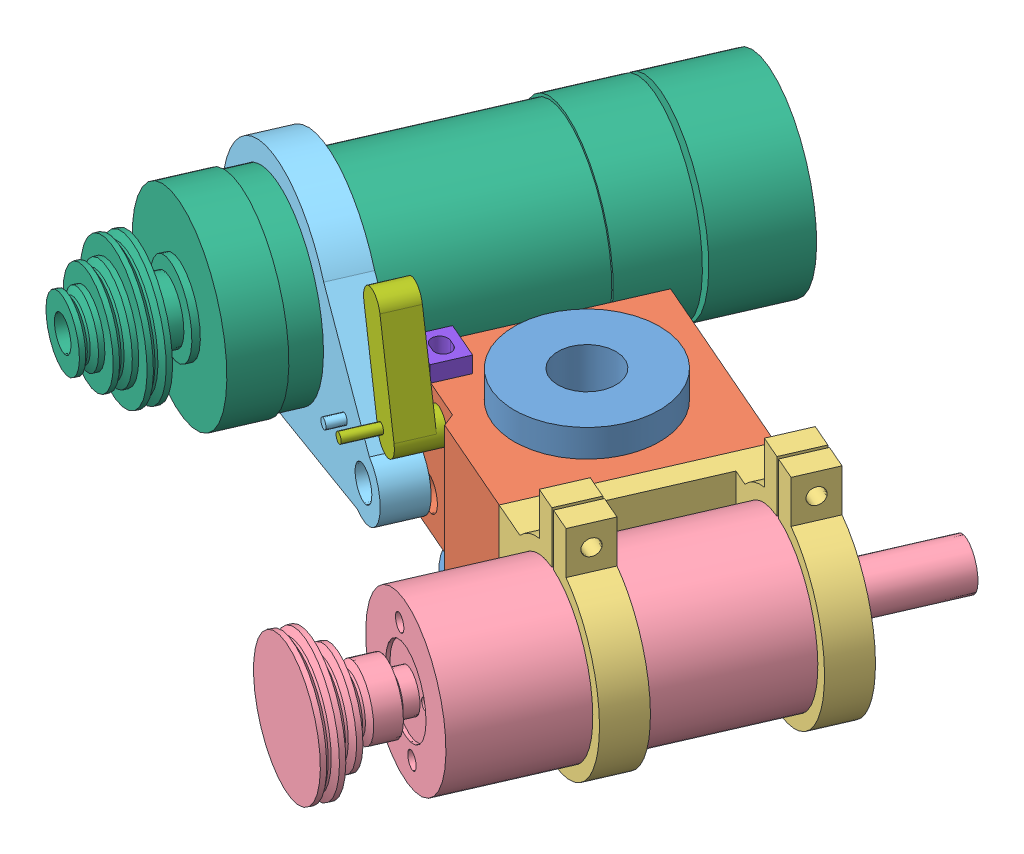
SolidWorks assembly Grinder Assembly, configuration Default. Lengths in mm.
Overall size (249.2 115.45 235.8).
8 component instances, 8 part files, 20 mates.
Components (placement in the parent):
- Center Boss-1: Center Boss [Default] at origin size (65 60 65)
- Grinder Base-1: Grinder Base [Default] at (0 11.5 0) x (-0.916958 0 -0.398985) z (0.398985 0 -0.916958) size (63 40 65)
- Spindle Clamp-1: Spindle Clamp [Default] at (56.9256 31.5 24.7694) x (0.916958 0 0.398985) z (-0.398985 0 0.916958) size (60 68 65)
- Spindle and Bearings and pulleys-1: Spindle and Bearings and pulleys [Default] at (50.1097 31.5 40.4339) x (-0.204426 0.974832 -0.08895) z (0.398985 0 -0.916958) size (48 48 160)
- Powered Spindle Bracket-1: Powered Spindle Bracket [Default] at (-83.8503 46.5162 12.0453) x (0.516913 -0.825961 0.224918) z (0.398985 0 -0.916958) size (88.55 75.05 17)
- Powered Spindle-2: Powered Spindle [Default] at (-70.717 46.5162 -18.1381) x (0.501751 0.837008 0.218321) z (-0.398985 0 0.916958) size (56.7 56.7 169.2)
- Cam Shaft-1: Cam Shaft [Default] at (-21.1566 43.5 14.7868) x (0.881169 0.276651 0.383413) z (-0.398985 0 0.916958) size (10 40.47 30)
- Belt tension-1: Belt tension [Default] at (-32.2527 51.5 12.8486) x (0.398985 0 -0.916958) z (0.916958 0 0.398985) size (15 5 12)
Mates (geometry in assembly coordinates):
- Concentric1: concentric anti-aligned: cylinder of Center Boss-1 through (0 60 0) axis (0 -1 0) radius 22.5; cylinder of Grinder Base-1 through (0 11.499 0) axis (0 1 0) radius 22.5
- Coincident1: coincident: plane of Grinder Base-1 through (25.2163 11.5 10.9721) normal (0.916958 0 0.398985); plane of Spindle Clamp-1 through (12.2493 31.5 40.7732) normal (-0.916958 0 -0.398985)
- Coincident2: coincident aligned: plane of Grinder Base-1 through (42.7681 51.5 -16.8341) normal (0.398985 0 -0.916958); plane of Spindle Clamp-1 through (69.8926 31.5 -5.0318) normal (0.398985 0 -0.916958)
- Coincident3: coincident aligned: plane of Grinder Base-1 through (0 51.5 0) normal (0 1 0); plane of Spindle Clamp-1 through (43.9586 51.5 54.5705) normal (0 1 0)
- Distance1: distance = 5.5 mm anti-aligned: plane of Grinder Base-1 through (0 11.5 0) normal (0 -1 0); plane of Center Boss-1 through (0 6 0) normal (0 1 0)
- Concentric2: concentric anti-aligned: cylinder of Spindle Clamp-1 through (43.9586 31.5 54.5705) axis (0.398985 0 -0.916958) radius 24; cylinder of Spindle and Bearings and pulleys-1 through (70.0589 31.5 -5.414) axis (-0.398985 0 0.916958) radius 24
- Concentric3: concentric: cylinder of Grinder Base-1 through (-38.3864 21.5 31.8275) axis (0.398985 0 -0.916958) radius 5; cylinder of Powered Spindle Bracket-1 through (-33.5986 21.5 20.824) axis (-0.398985 0 0.916958) radius 5
- Coincident5: coincident: plane of Grinder Base-1 through (-38.3864 21.5 31.8275) normal (-0.398985 0 0.916958); plane of Powered Spindle Bracket-1 through (-87.9388 47.5705 10.2663) normal (-0.398985 0 0.916958)
- Parallel1: parallel aligned: plane of Powered Spindle Bracket-1 through (-83.8503 46.5162 12.0453) normal (-0.398985 0 0.916958); plane of Powered Spindle-2 through (-102.6539 53.3561 29.0371) normal (-0.398985 0 0.916958)
- Concentric5: concentric aligned: cylinder of Powered Spindle Bracket-1 through (-79.0625 46.5162 1.0418) axis (-0.398985 0 0.916958) radius 27.5; cylinder of Powered Spindle-2 through (-109.3987 46.5162 70.7613) axis (-0.398985 0 0.916958) radius 27.5
- Coincident7: coincident aligned: plane of Spindle and Bearings and pulleys-1 through (23.4583 32.6147 113.9013) normal (-0.398985 0 0.916958); plane of Powered Spindle-2 through (-111.7072 51.9881 55.0883) normal (-0.398985 0 0.916958)
- Belt Length 125/135: limit distance = 135 mm: line of Powered Spindle-2 through (-104.0322 46.5162 58.4278) axis (0.398985 0 -0.916958); line of Spindle and Bearings and pulleys-1 through (18.9889 31.5 111.9565) axis (0.398985 0 -0.916958)
- LimitDistance2: limit distance = 0.4169 mm aligned: plane of Spindle and Bearings and pulleys-1 through (70.0589 31.5 -5.414) normal (0.398985 0 -0.916958); plane of Spindle Clamp-1 through (69.8926 31.5 -5.0318) normal (0.398985 0 -0.916958)
- LimitDistance4: limit distance = 8.4831 mm anti-aligned: plane of Powered Spindle-2 through (-108.9936 62.0291 10.3563) normal (0.398985 0 -0.916958); plane of Powered Spindle Bracket-1 through (-83.8503 46.5162 12.0453) normal (-0.398985 0 0.916958)
- Concentric9: concentric anti-aligned: cylinder of Grinder Base-1 through (-21.1566 43.5 14.7868) axis (-0.398985 0 0.916958) radius 5; cylinder of Cam Shaft-1 through (-29.1363 43.5 33.1259) axis (0.398985 0 -0.916958) radius 5
- Coincident13: coincident anti-aligned: plane of Grinder Base-1 through (-8.7777 11.5 20.1731) normal (-0.398985 0 0.916958); plane of Cam Shaft-1 through (-21.1566 43.5 14.7868) normal (0.398985 0 -0.916958)
- Distance10: distance = 16.9065 mm: line of Cam Shaft-1 through (-35.8446 43.9593 41.1127) axis (0.398985 0 -0.916958); line of Powered Spindle Bracket-1 through (-48.9793 37.0097 32.6711) axis (0.398985 0 -0.916958)
- Distance12: distance = 0.25 mm anti-aligned: cylinder of Grinder Base-1 through (-34.9915 41.5 11.4934) axis (0 1 0) radius 2.1; plane of Belt tension-1 through (-30.3383 56.5 10.9552) normal (-0.398985 0 0.916958)
- Coincident17: coincident anti-aligned: plane of Grinder Base-1 through (0 51.5 0) normal (0 1 0); plane of Belt tension-1 through (-32.2527 51.5 12.8486) normal (0 -1 0)
- Parallel7: parallel anti-aligned: plane of Grinder Base-1 through (-11.7701 11.5 27.0502) normal (-0.398985 0 0.916958); plane of Belt tension-1 through (-35.7596 56.5 5.8699) normal (0.398985 0 -0.916958)
